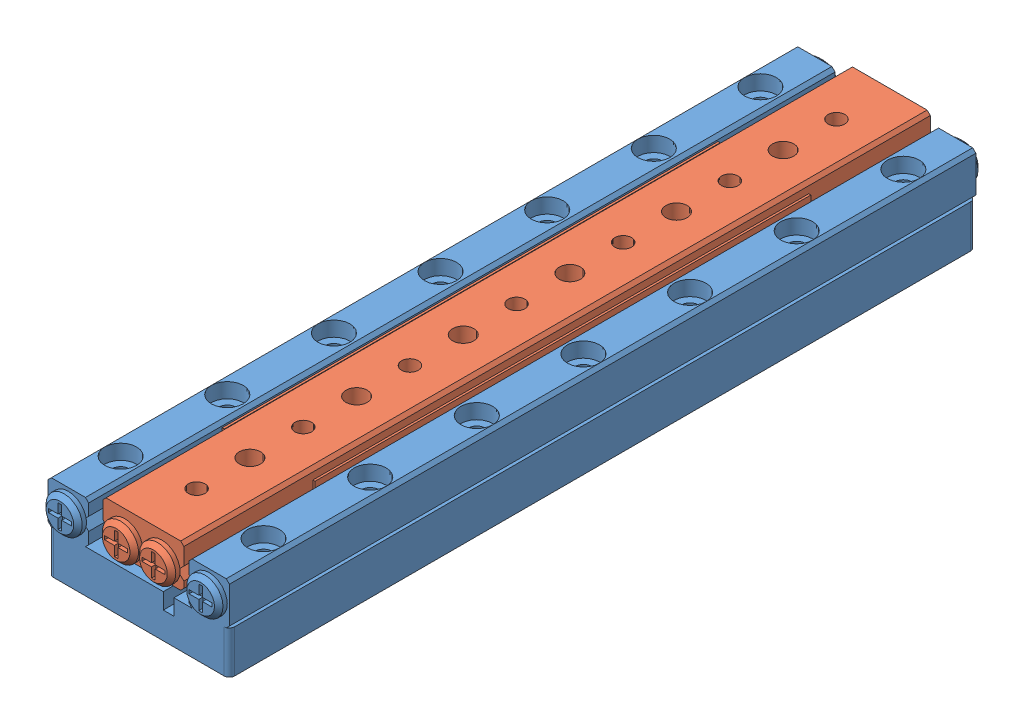
SolidWorks assembly SmarAct_SLC1770, configuration Default. Lengths in mm.
Overall size (17 8.5 72.03).
2 component instances, 2 part files, 6 mates.
Components (placement in the parent):
- SmarAct_SLC1770_base-1: SmarAct_SLC1770_base [Default] at (17 39.7859 -882.6842) x (1 0 0) z (0 -1 0) size (17 71.6 8)
- SmarAct_SLC1770_slide-1: SmarAct_SLC1770_slide [Default] at (17 39.7862 -883.1109) x (1 0 0) z (0 -1 0) size (8.7 71.6 4.4)
Mates (geometry in assembly coordinates):
- Coincident2: coincident anti-aligned: plane of SmarAct_SLC1770_base-1 through (8.5 0 35) normal (0 -1 0); plane of assembly through (0 0 0) normal (0 1 0)
- Coincident3: coincident anti-aligned: plane of SmarAct_SLC1770_base-1 through (3.6125 4 0) normal (0 0 -1); plane of assembly through (0 0 0) normal (0 0 1)
- Coincident4: coincident anti-aligned: plane of SmarAct_SLC1770_base-1 through (0 6 70) normal (-1 0 0); plane of assembly through (0 0 0) normal (1 0 0)
- Coincident5: coincident aligned: plane of SmarAct_SLC1770_base-1 through (1.275 5.8298 70.8) normal (0 1 0); plane of SmarAct_SLC1770_slide-1 through (6.1325 5.8298 70.3733) normal (0 1 0)
- LimitDistance1: limit distance = -0.4267 mm aligned: plane of SmarAct_SLC1770_slide-1 through (8.5 6.4788 69.5733) normal (0 0 1); plane of SmarAct_SLC1770_base-1 through (11.6125 4 70) normal (0 0 1)
- Coincident6: coincident aligned: plane of SmarAct_SLC1770_base-1; plane of SmarAct_SLC1770_slide-1
